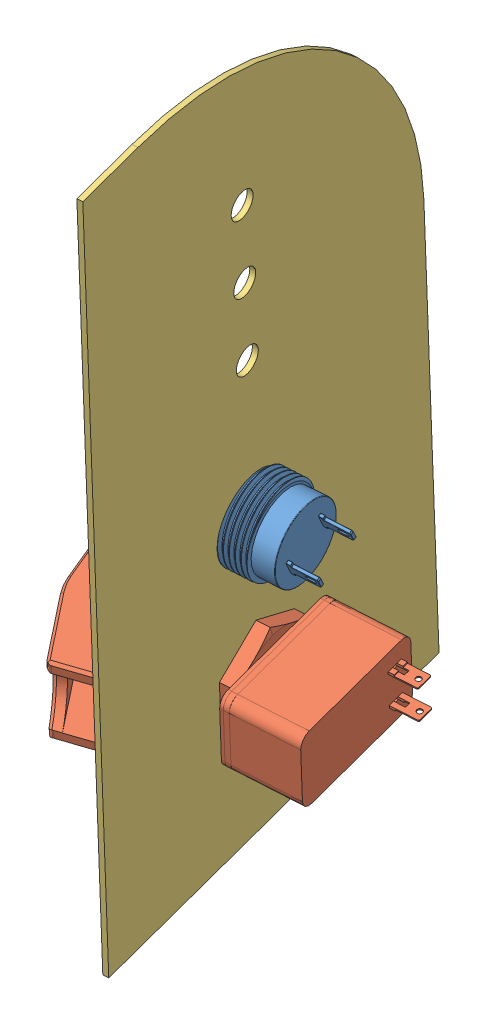
SolidWorks assembly PUTM-G-DS-Right-Plate-Ass, configuration Domyślna. Lengths in mm.
Overall size (61.76 159.52 95.15).
3 component instances, 3 part files, 3 mates.
Components (placement in the parent):
- PUTM-G-DS-Button_Drucktaster R13-507 rot v7-1: PUTM-G-DS-Button_Drucktaster R13-507 rot v7 [Domyślna] at (-158.537 -189.6343 551.3633) x (0.08944 -0.49464 0.864483) z (-0.984217 0.089177 0.152853) size (22.86 21.44 24.86)
- PUTM-G-DS-Toggle Switch-1: PUTM-G-DS-Toggle Switch [Domyślna] at (-171.7437 -218.2883 548.4654) x (-0.137396 0.159292 -0.977624) z (0.11153 0.983196 0.144525) size (51.99 53.27 19.63)
- PUTM-G-DS-Right_plate_leds-1: PUTM-G-DS-Right_plate_leds [Domyślna] at (-169.2965 -253.4485 578.1936) x (-0.11153 -0.983196 -0.144525) z (-0.984217 0.089177 0.152853) size (150 75 1)
Mates (geometry in assembly coordinates):
- Koncentryczne6: concentric aligned: circle of Toggle Switch-1; circle of PUTM-G-DS-Right_plate_leds-1
- Wspólnie8: coincident anti-aligned: plane of Toggle Switch-1 through (-174.7527 -224.256 532.5725) normal (0.984217 -0.089177 -0.152853); plane of PUTM-G-DS-Right_plate_leds-1 through (-167.0684 -173.6462 552.5249) normal (-0.984217 0.089177 0.152853)
- Odległość7: distance = 0 mm anti-aligned: plane of Drucktaster R13-507 rot v7-1 through (-168.3792 -188.7425 552.8918) normal (0.984217 -0.089177 -0.152853); plane of PUTM-G-DS-Right_plate_leds-1 through (-167.0684 -173.6462 552.5249) normal (-0.984217 0.089177 0.152853)
